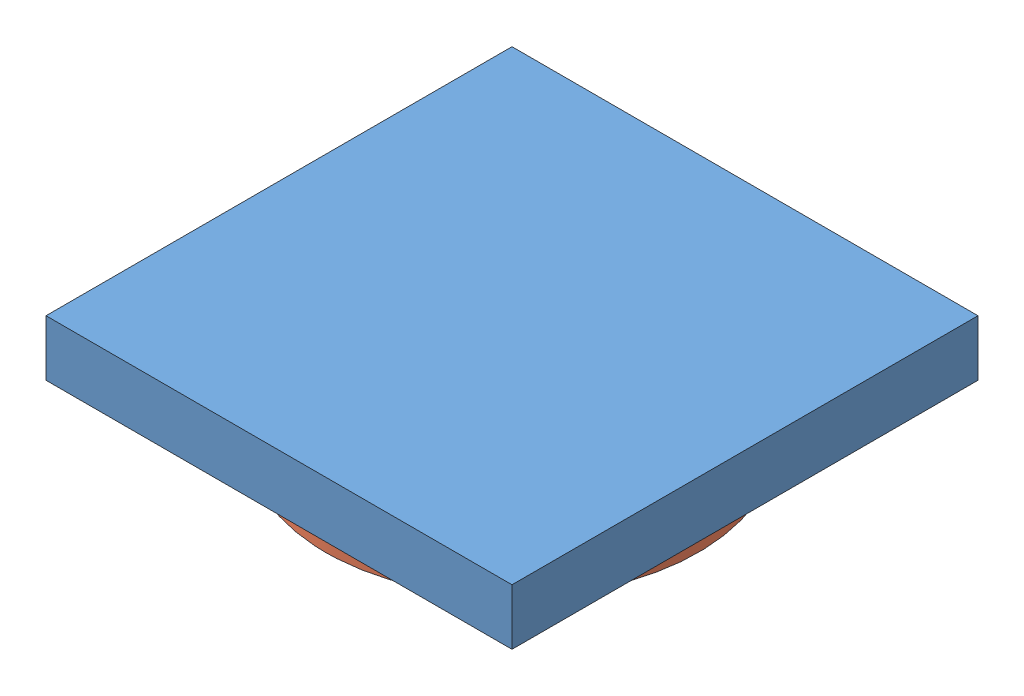
SolidWorks assembly C_10m_5t_mold_top, configuration Default. Lengths in mm.
Overall size (25 6 25).
2 component instances, 2 part files, 2 mates.
Components (placement in the parent):
- 25x25x5_block-1: 25x25x5_block [Default] at (7.8154 11.3541 20.1205) size (25 3 25)
- C_10m_5t-1: C_10m_5t [Default] at (7.8154 8.3541 20.1205) size (20 5 20)
Mates (geometry in assembly coordinates):
- Coincident1: coincident anti-aligned: plane of 25x25x5_block-1 through (7.8154 11.3541 20.1205) normal (0 -1 0); plane of C_10m_5t-1 through (7.8154 11.3541 20.1205) normal (0 1 0)
- Coincident2: coincident: line of C_10m_5t-1 through (7.8154 13.3541 20.1205) axis (0 -1 0)
